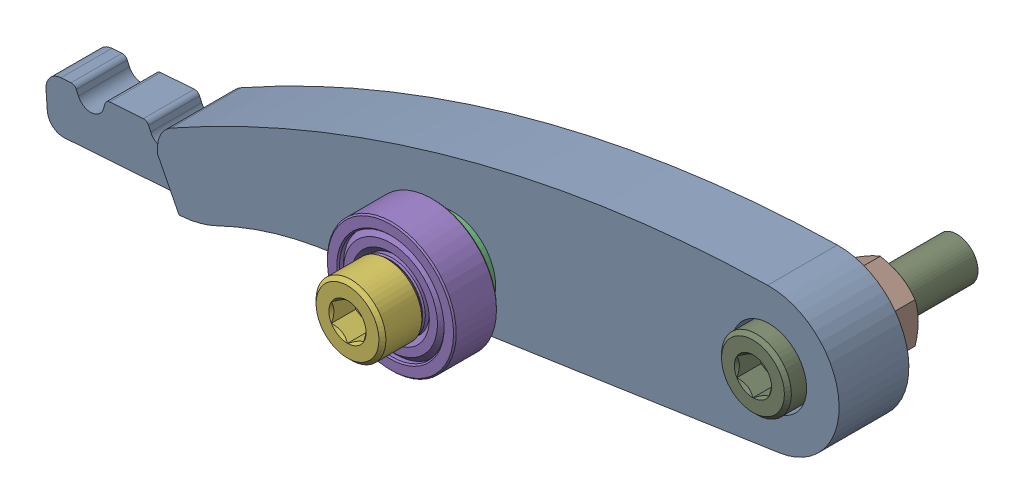
SolidWorks assembly MFG CW Pressure Arm Asmbly, configuration Default. Lengths in mm.
Overall size (151.28 45.24 54.95).
9 component instances, 6 part files, 0 mates.
Components (placement in the parent):
- MFG CW Pressure Arm-1: MFG CW Pressure Arm [Default] at origin size (151.28 45.24 13)
- M8 x 1.25 Hex Nut-1: M8 x 1.25 Hex Nut [Default] at (0 230.1 39.55) x (0 -1 0) z (0 0 1) size (13 15.01 6.5)
- 8.4mm ID 16mm OD Flat Washer-1: 8.4mm ID 16mm OD Flat Washer [Default] at (0 230.1 47.8) size (16 16 1.8)
- 8.4mm ID 16mm OD Flat Washer-2: 8.4mm ID 16mm OD Flat Washer [Default] at (0 230.1 49.6) size (16 16 1.8)
- 628Z 8x24x8mm Ball Bearing-1: 628Z 8x24x8mm Ball Bearing [Default] at (0 230.1 55.4) size (24 24 8)
- M8 x 1.5 mm 25 mm Length Socket Head Screw-1: M8 x 1.5 mm 25 mm Length Socket Head Screw [Default] at (0 230.1 59.4) size (13 13 33.35)
- 8.4mm ID 16mm OD Flat Washer-3: 8.4mm ID 16mm OD Flat Washer [Default] at (58.9473 242.5 33) size (16 16 1.8)
- M8 x 1.25 Hex Nut-2: M8 x 1.25 Hex Nut [Default] at (58.9473 242.5 29.75) size (13 15.01 6.5)
- M8 x 1.5 mm 30 mm Length Socket Head Screw v1-1: M8 x 1.5 mm 30 mm Length Socket Head Screw v1 [Default] at (58.9473 242.5 42.8) size (13 13 38.35)
